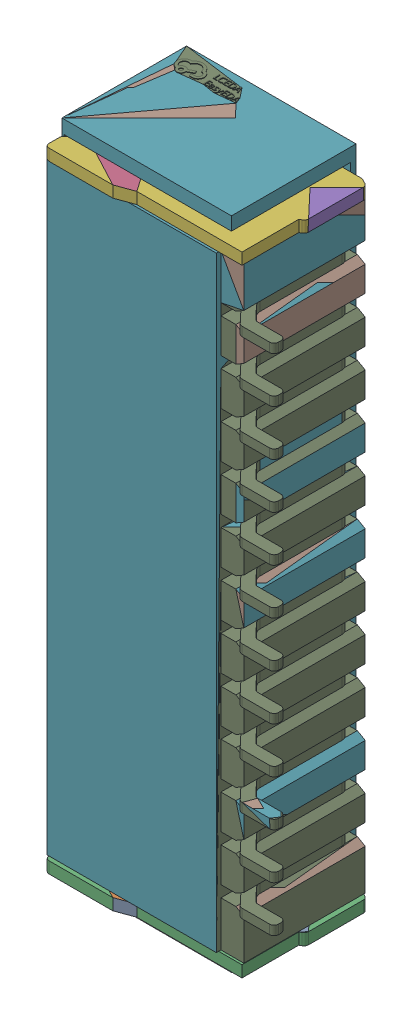
SolidWorks assembly CN3, configuration Défaut. Lengths in mm.
Overall size (5.05 14.31 3.14).
9 component instances, 6 part files, 0 mates.
Components (placement in the parent):
- HC-1.0-12PWT-1: HC-1.0-12PWT [Défaut] at (10.1 -18.2167 -0.4818) x (0 1 0) z (0 0 -1) size (0.25 4.26 2.84)
- HC-1.0-12PWT-2: HC-1.0-12PWT [Défaut] at (10.1 -18.2167 -0.4818) x (0 1 0) z (0 0 -1) size (0.25 4.26 2.84)
- HC-1.0-12PWT_1157-1: HC-1.0-12PWT_1157 [Défaut] at (10.1 -18.2167 -0.4818) x (0 1 0) z (0 0 -1) size (0.25 4.26 2.84)
- HC-1.0-12PWT_1159-1: HC-1.0-12PWT_1159 [Défaut] at (10.1 -18.2167 -0.4818) x (0 1 0) z (0 0 -1) size (0.25 4.26 2.84)
- HC-1.0-12PWT_1159-2: HC-1.0-12PWT_1159 [Défaut] at (10.1 -18.2167 -0.4818) x (0 1 0) z (0 0 -1) size (0.25 4.26 2.84)
- HC-1.0-12PWT_1162-1: HC-1.0-12PWT_1162 [Défaut] at (10.1 -18.2167 -0.4818) x (0 1 0) z (0 0 -1) size (0.25 4.26 2.84)
- HC-1.0-12PWT_1164-1: HC-1.0-12PWT_1164 [Défaut] at (10.1 -18.2167 -0.4818) x (0 1 0) z (0 0 -1) size (14.31 5.05 3.14)
- HC-1.0-12PWT_1164-2: HC-1.0-12PWT_1164 [Défaut] at (10.1 -18.2167 -0.4818) x (0 1 0) z (0 0 -1) size (14.31 5.05 3.14)
- HC-1.0-12PWT_1167-1: HC-1.0-12PWT_1167 [Défaut] at (10.1 -18.2167 -0.4818) x (0 1 0) z (0 0 -1) size (14.31 5.05 3.14)
